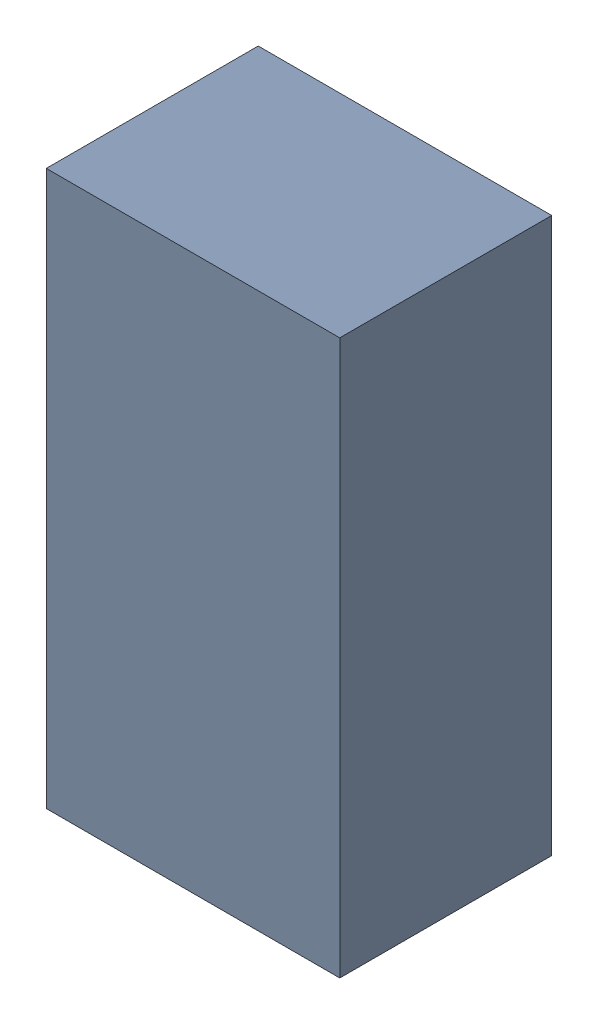
SolidWorks assembly C1, configuration Default. Lengths in mm.
Overall size (1.8 3.4 1.3).
2 component instances, 1 part files, 0 mates.
Components (placement in the parent):
- 5920131968-1: 5920131968 [Default] at (32.5 40.75 0) size (1.8 3.4 1.3)
  - Extruded_2-1: Extruded_2 [Default] at origin size (1.8 3.4 1.3)
